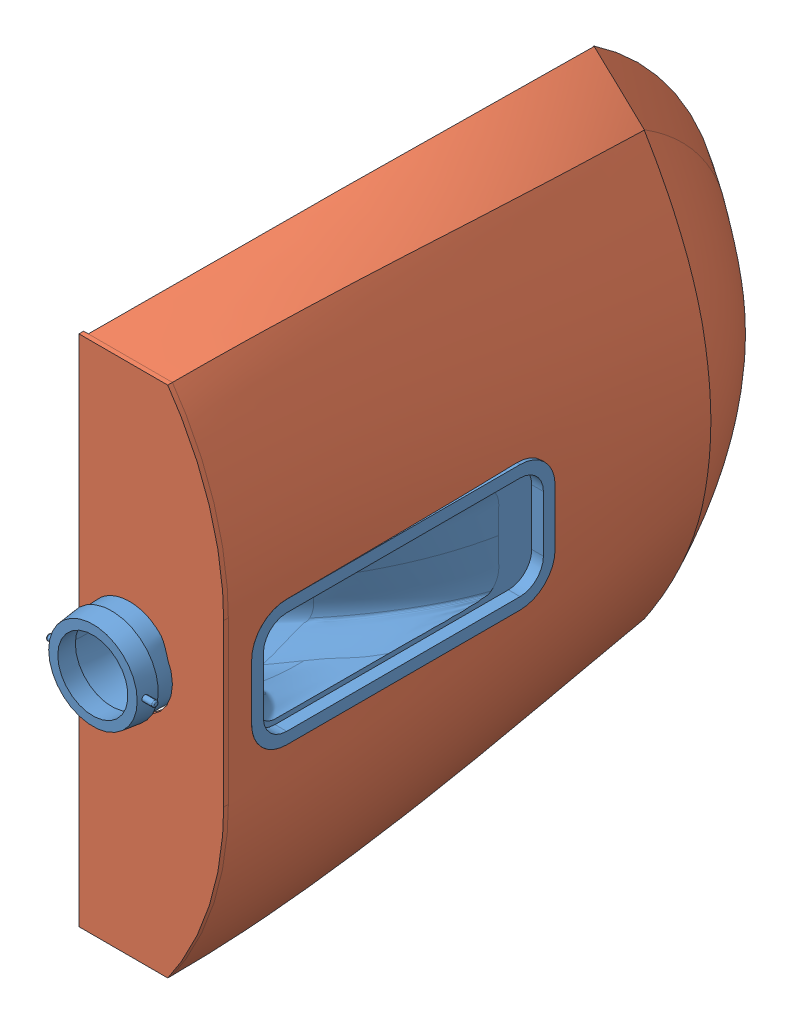
SolidWorks assembly AssembleBaseTurbine, configuration Default. Lengths in mm.
Overall size (68.8 225.14 293.75).
2 component instances, 2 part files, 3 mates.
Components (placement in the parent):
- Turbine sketch-1: Turbine sketch [Default] at (56.2164 93.1548 186.2375) size (64 54 158.04)
- BottonCover-1: BottonCover [Default] at (1.2164 91.1548 201.2375) x (0 0 1) z (0 -1 0) size (277.71 67.81 225.14)
Mates (geometry in assembly coordinates):
- Coincident4: coincident anti-aligned: plane of Turbine sketch-1 through (61.2164 81.1548 61.2375) normal (0 0 -1); plane of BottonCover-1 through (82.2164 101.1548 61.2375) normal (0 0 1)
- Coincident5: coincident anti-aligned: plane of Turbine sketch-1 through (61.2164 66.1548 176.2375) normal (0 -1 0); plane of BottonCover-1 through (82.2164 66.1548 76.2375) normal (0 1 0)
- Tangent4: tangent aligned: plane of Turbine sketch-1 through (61.2164 81.1548 176.2375) normal (1 0 0); face of BottonCover-1
